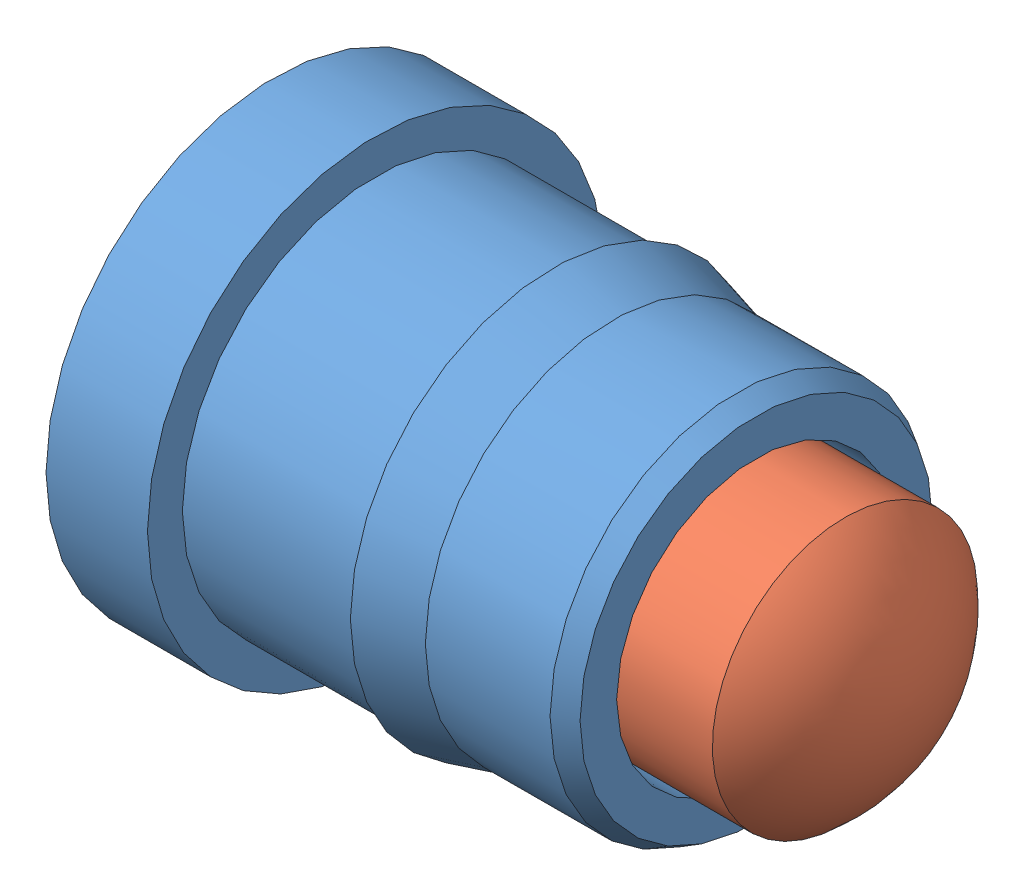
SolidWorks assembly mill-max-0965-0-15-20-80-14-11-0, configuration default. Lengths in mm.
Overall size (2.54 1.83 1.83).
4 component instances, 4 part files, 5 mates.
Components (placement in the parent):
- mill-max-0965-0-15-20-80-14-11-0_6995-0-1: mill-max-0965-0-15-20-80-14-11-0_6995-0 [6995-0-02-20-00-00-13-0] at origin size (1.93 1.83 1.83)
- mill-max-0965-0-15-20-80-14-11-0_9318-0-1: mill-max-0965-0-15-20-80-14-11-0_9318-0 [9318-0-00-20-00-00-13-0] at (1.0922 0 0) x (1 0 0) z (0 0.794749 0.606938) size (1.45 1.25 1.25)
- mill-max-0965-0-15-20-80-14-11-0_9305-0-1: mill-max-0965-0-15-20-80-14-11-0_9305-0 [9305-0-00-20-00-00-13-0] at origin size (1.27 1.31 1.31)
- mill-max-0965-0-15-20-80-14-11-0_SPRING-1: mill-max-0965-0-15-20-80-14-11-0_SPRING [6880-0-00-00-80-14-43-1] at (0.5322 0 0) x (0 0.966326 0.257319) z (1 0 0) size (0.8 0.89 1.82)
Mates (geometry in assembly coordinates):
- Concentric1: concentric: cylinder of ? through (0 0 0) axis (-1 0 0) radius 0.6477; cylinder of mill-max-0965-0-15-20-80-14-11-0_9318-0-1 through (1.0922 0 0) axis (-1 0 0) radius 0.6236
- Concentric2: concentric: cylinder of ? through (0 0 0) axis (-1 0 0) radius 0.6477; cylinder of mill-max-0965-0-15-20-80-14-11-0_9305-0-1 through (0 0 0) axis (-1 0 0) radius 0.6541
- Coincident1: coincident: circle of ?; plane of mill-max-0965-0-15-20-80-14-11-0_9305-0-1 through (0 0 0) normal (-1 0 0)
- Distance2: distance = 0.6096 mm: point of mill-max-0965-0-15-20-80-14-11-0_9318-0-1; plane of ? through (1.9304 0.7053 0) normal (1 0 0)
- Concentric3: concentric: cylinder of mill-max-0965-0-15-20-80-14-11-0_9305-0-1 through (0 0 0) axis (-1 0 0) radius 0.2032; line of mill-max-0965-0-15-20-80-14-11-0_SPRING-1 through (0.2571 0 0) axis (1 0 0)
